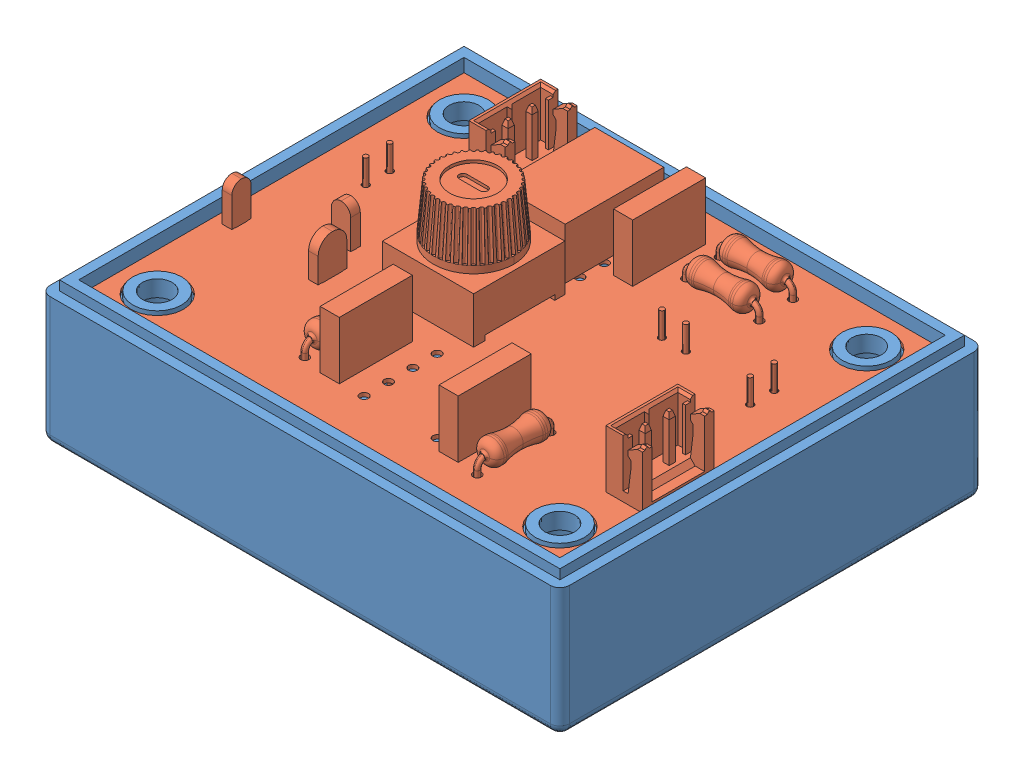
SolidWorks assembly Assemblage21, configuration Défaut. Lengths in mm.
Overall size (55.14 23.62 44.2).
2 component instances, 2 part files, 3 mates.
Components (placement in the parent):
- piècebas-1: piècebas [Défaut] at (-85.7489 16.2493 5.2569) size (54.2 14.5 44.2)
- carte_pcb.step-2: carte_pcb.step [Défaut] at (-108.7074 29.4608 19.9) x (1 0 0) z (0 1 0) size (53.04 40 22.42)
Mates (geometry in assembly coordinates):
- Coaxiale10: concentric anti-aligned: circle of carte_pcb.step-2; circle of piècebas-1
- Coaxiale11: concentric anti-aligned: circle of piècebas-1; circle of carte_pcb.step-2
- Coïncidente12: coincident anti-aligned: plane of piècebas-1 through (-61.1574 29.0493 15.9) normal (0 1 0); plane of carte_pcb.step-2 through (-83.7074 29.0493 -0.1) normal (0 -1 0)
